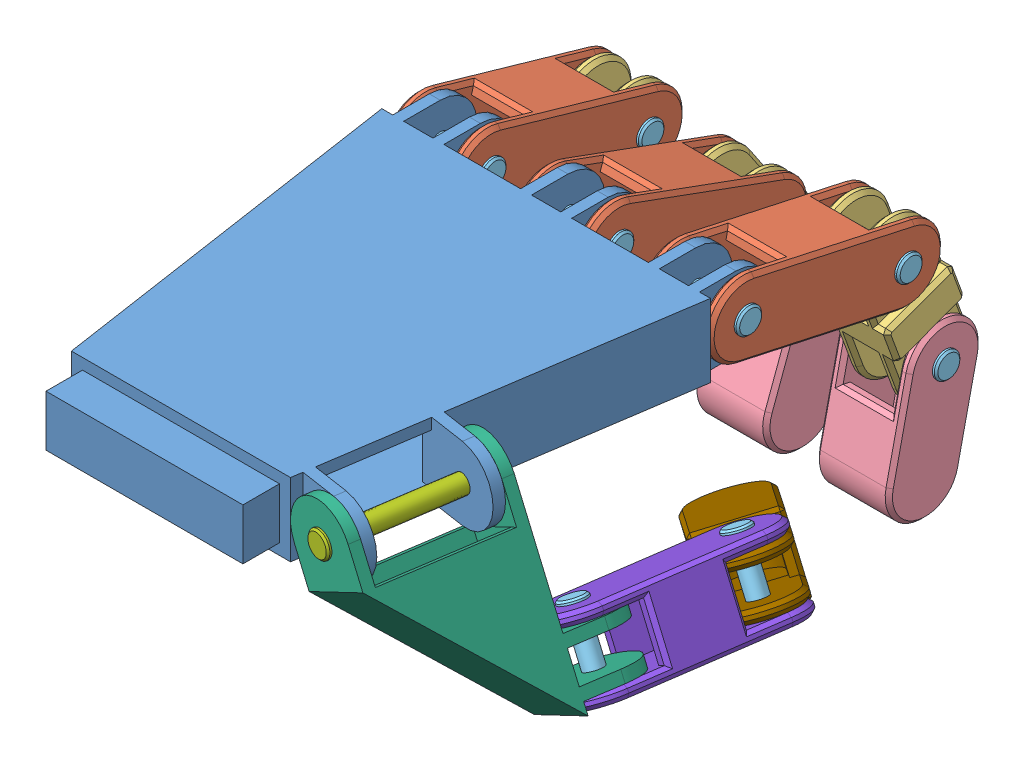
SolidWorks assembly Robot_Hand_Left, configuration Default. Lengths in mm.
Overall size (139 98.15 202.96).
29 component instances, 9 part files, 21 mates.
Components (placement in the parent):
- hand_palm_left-1: hand_palm_left [Default] at origin size (100.27 20 130)
- Robot_Finger-1: Robot_Finger [Default] at (35 0 -10) x (0 0.213225 0.977003) z (-1 0 0) size (84.9 74.17 22) (flexible)
  - finger_inner-1: finger_inner [Default] at (-22.5 0 0) x (-1 0 0) z (0 0 -1) size (65 20 20)
  - finger_middle-1: finger_middle [Default] at (-53.0486 -12.6578 0) x (-0.536574 -0.843853 0) z (0 0 -1) size (50 20 20)
  - finger_top-1: finger_top [Default] at (-61.0395 -37.8155 0) x (0.004615 -0.999989 0) z (0 0 -1) size (45 20 20)
  - finger_connector-1: finger_connector [Default] x (1 0 0) z (0 0 -1) size (7 7 22)
  - finger_connector-2: finger_connector [Default] at (-45 0 0) x (0.843853 -0.536574 0) z (0 0 -1) size (7 7 22)
  - finger_connector-3: finger_connector [Default] at (-61.0972 -25.3156 0) x (0.004615 -0.999989 0) z (0 0 -1) size (7 7 22)
- Robot_Finger-2: Robot_Finger [Default] at (0 0 -10) x (0 0.343168 0.939274) z (-1 0 0) size (93.22 66.67 22) (flexible)
  - finger_inner-1: finger_inner [Default] at (-22.5 0 0) x (-1 0 0) z (0 0 -1) size (65 20 20)
  - finger_middle-1: finger_middle [Default] at (-57.1246 -8.8315 0) x (-0.808304 -0.588765 0) z (0 0 -1) size (50 20 20)
  - finger_top-1: finger_top [Default] at (-69.1984 -30.1629 0) x (0.004054 -0.999992 0) z (0 0 -1) size (45 20 20)
  - finger_connector-1: finger_connector [Default] x (1 0 0) z (0 0 -1) size (7 7 22)
  - finger_connector-2: finger_connector [Default] at (-45 0 0) x (0.588765 -0.808304 0) z (0 0 -1) size (7 7 22)
  - finger_connector-3: finger_connector [Default] at (-69.2491 -17.663 0) x (0.004054 -0.999992 0) z (0 0 -1) size (7 7 22)
- Robot_Finger-3: Robot_Finger [Default] at (-35 0 -10) x (0 0.276691 0.960959) z (-1 0 0) size (83.29 76.95 22) (flexible)
  - finger_inner-1: finger_inner [Default] at (-22.5 0 0) x (-1 0 0) z (0 0 -1) size (65 20 20)
  - finger_middle-1: finger_middle [Default] at (-50.9409 -13.7734 0) x (-0.396057 -0.918226 0) z (0 0 -1) size (50 20 20)
  - finger_top-1: finger_top [Default] at (-59.2354 -39.8232 0) x (-0.188295 -0.982113 0) z (0 0 -1) size (45 20 20)
  - finger_connector-1: finger_connector [Default] x (1 0 0) z (0 0 -1) size (7 7 22)
  - finger_connector-2: finger_connector [Default] at (-45 0 0) x (0.918226 -0.396057 0) z (0 0 -1) size (7 7 22)
  - finger_connector-3: finger_connector [Default] at (-56.8817 -27.5468 0) x (-0.188295 -0.982113 0) z (0 0 -1) size (7 7 22)
- thumb_plate-1: thumb_plate [Default] at (44.6516 -8.7642 102.1977) x (0.476226 -0.876417 0.071434) z (-0.14834 0 0.988936) size (60 20 60)
- thumb_plate_connector-1: thumb_plate_connector [Default] at (42.8562 0 81.7047) x (0.476226 -0.876417 0.071434) z (-0.14834 0 0.988936) size (7 7 42)
- Robot_Thumb-1: Robot_Thumb [Default] at (66.3554 -35.0567 54.8939) x (0.133192 -0.008404 -0.991055) z (0.476226 -0.876417 0.071434) size (81.4 57.56 22) (flexible)
  - thumb_inner-1: thumb_inner [Default] at (20 0 0) size (60 20 20)
  - thumb_top-1: thumb_top [Default] at (48.8569 -15.0932 0) x (0.506106 -0.862471 0) z (0 0 1) size (55 20 20)
  - finger_connector-1: finger_connector [Default] at origin size (7 7 22)
  - finger_connector-2: finger_connector [Default] at (40 0 0) x (0.506106 -0.862471 0) z (0 0 1) size (7 7 22)
Mates (geometry in assembly coordinates):
- Coincident1: coincident aligned: plane of hand_palm_left-1 through (0 0 0) normal (0 0 1)
- Coincident2: coincident aligned: plane of hand_palm_left-1 through (0 0 0) normal (0 1 0)
- Coincident3: coincident aligned: plane of hand_palm_left-1 through (0 0 0) normal (1 0 0)
- Concentric1: concentric aligned: cylinder of hand_palm_left-1 through (42 0 -10) axis (-1 0 0) radius 2.5; cylinder of Robot_Finger-1/finger_connector-1 through (45 0 -10) axis (-1 0 0) radius 2.5
- Coincident5: coincident anti-aligned: plane of hand_palm_left-1 through (42 0 -10) normal (1 0 0); plane of Robot_Finger-1/finger_inner-1 through (42 0 -10) normal (-1 0 0)
- LimitAngle1: limit planar angle = 0.214874 rad aligned: plane of Robot_Finger-1 through (35 0 -10) normal (0 0.213225 0.977003)
- Coincident7: coincident anti-aligned: circle of hand_palm_left-1; cylinder of Robot_Finger-2/finger_connector-1 through (10 0 -10) axis (-1 0 0) radius 2.5
- Coincident8: coincident anti-aligned: plane of hand_palm_left-1 through (-7 0 -10) normal (-1 0 0); plane of Robot_Finger-2/finger_inner-1 through (-7 0 -10) normal (1 0 0)
- LimitAngle2: limit planar angle = 0.350287 rad aligned: plane of Robot_Finger-2 through (0 0 -10) normal (0 0.343168 0.939274)
- Concentric2: concentric aligned: cylinder of hand_palm_left-1 through (-28 0 -10) axis (-1 0 0) radius 2.5; cylinder of Robot_Finger-3/finger_connector-1 through (-25 0 -10) axis (-1 0 0) radius 2.5
- Coincident10: coincident anti-aligned: plane of hand_palm_left-1 through (-28 0 -10) normal (1 0 0); plane of Robot_Finger-3/finger_inner-1 through (-28 0 -10) normal (-1 0 0)
- LimitAngle3: limit planar angle = 0.280349 rad aligned: plane of Robot_Finger-3 through (-35 0 -10) normal (0 0.276691 0.960959)
- Concentric3: concentric anti-aligned: cylinder of hand_palm_left-1 through (45.378 0 64.8928) axis (-0.14834 0 0.988936) radius 2.5; cylinder of thumb_plate_connector-1 through (39.8894 0 101.4834) axis (0.14834 0 -0.988936) radius 2.5
- Concentric4: concentric anti-aligned: cylinder of thumb_plate-1 through (40.3344 0 98.5166) axis (-0.14834 0 0.988936) radius 2.5; cylinder of thumb_plate_connector-1 through (39.8894 0 101.4834) axis (0.14834 0 -0.988936) radius 2.5
- Coincident11: coincident anti-aligned: plane of thumb_plate-1 through (39.8894 0 101.4834) normal (-0.14834 0 0.988936); plane of thumb_plate_connector-1 through (39.8894 0 101.4834) normal (0.14834 0 -0.988936)
- Coincident12: coincident anti-aligned: plane of hand_palm_left-1 through (40.3344 0 98.5166) normal (-0.14834 0 0.988936); plane of thumb_plate-1 through (40.3344 0 98.5166) normal (0.14834 0 -0.988936)
- Coincident14: coincident aligned: plane of thumb_plate-1 through (44.6516 -8.7642 102.1977) normal (0.86672 0.481554 0.130008); plane of thumb_plate_connector-1 through (42.8562 0 81.7047) normal (0.86672 0.481554 0.130008)
- LimitAngle4: limit planar angle = 1.06837 rad aligned: plane of thumb_plate_connector-1 through (42.8562 0 81.7047) normal (0.476226 -0.876417 0.071434); plane of hand_palm_left-1 through (45 10 0) normal (0.988936 0 0.14834)
- Concentric5: concentric aligned: cylinder of thumb_plate-1 through (71.1177 -43.8208 55.6083) axis (-0.476226 0.876417 -0.071434) radius 2.5; cylinder of Robot_Thumb-1/finger_connector-1 through (71.1177 -43.8208 55.6083) axis (-0.476226 0.876417 -0.071434) radius 2.5
- Coincident16: coincident anti-aligned: plane of thumb_plate-1 through (69.689 -41.1916 55.394) normal (0.476226 -0.876417 0.071434); plane of Robot_Thumb-1/thumb_inner-1 through (69.689 -41.1916 55.394) normal (-0.476226 0.876417 -0.071434)
- LimitAngle5: limit planar angle = 0.017453 rad anti-aligned: plane of Robot_Thumb-1 through (66.3554 -35.0567 54.8939) normal (0.133192 -0.008404 -0.991055); plane of thumb_plate-1 through (44.6516 -8.7642 102.1977) normal (-0.14834 0 0.988936)
